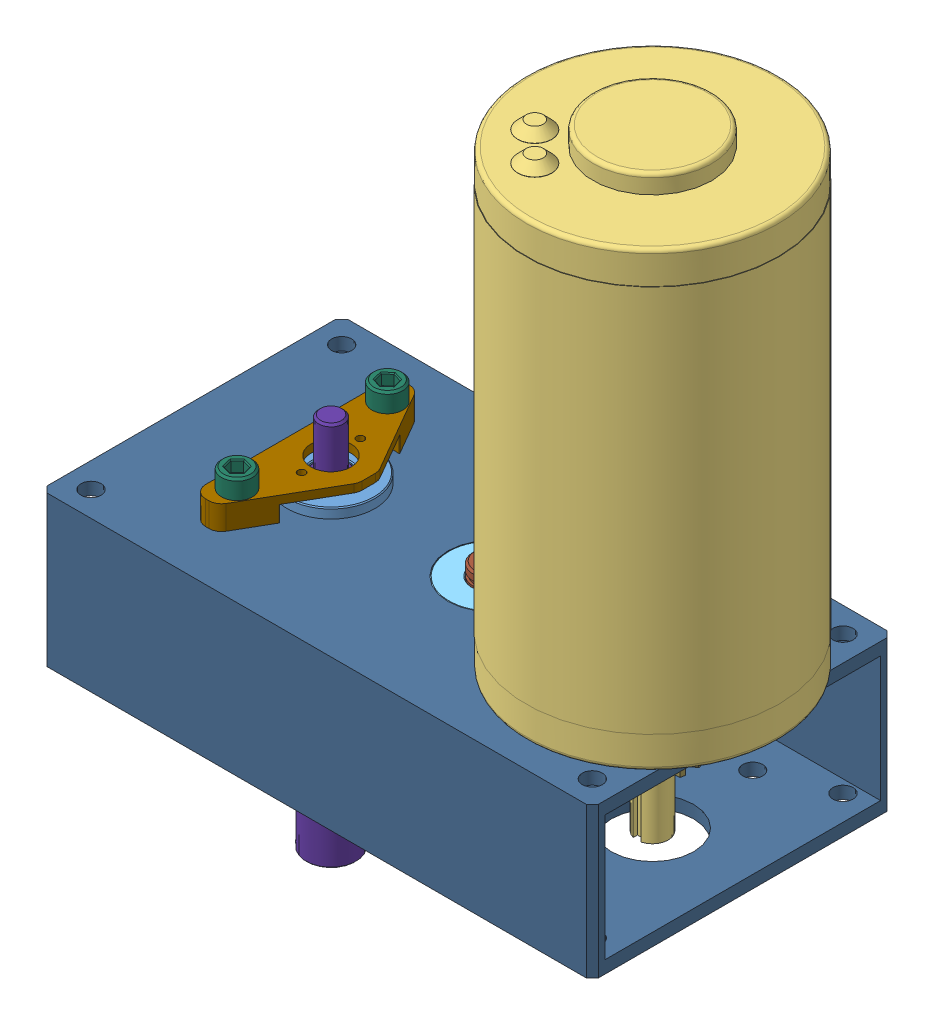
SolidWorks assembly Toughbox Nano 500 key, configuration Default. Lengths in mm.
Overall size (155.61 199.38 84.31).
20 component instances, 17 part files, 0 mates.
Components (placement in the parent):
- fr-6-zz-1: fr-6-zz [Default] at (44.2691 14.351 6.042) x (1 0 0) z (0 1 0) size (24.69 24.69 7.16)
- fr8zz-hex-1: fr8zz-hex [Default] at (35.4076 -22.2783 0) x (0.98361 0 -0.180311) z (0 1 0) size (31.12 31.12 7.93)
- CIM motor-1: CIM motor [Default] at (226.1362 38.1 -35.56) x (0 0 1) z (0 -1 0) size (64.01 64.01 154.95)
- fr-6-zz-hex-1: fr-6-zz-hex [Default] at (84.883 -14.351 -6.1894) x (0.99986 0 -0.016728) z (0 -1 0) size (24.69 24.69 7.75)
- fr-6-1: fr-6 [Default] at (86.7029 13.5128 -1.7646) x (0.722285 0 -0.691595) z (0 1 0) size (24.69 24.69 5.54)
- Toughbox_d05-1: Toughbox_d05 [Default] at (76.1238 3.3528 0) x (-0.016728 0 -0.99986) z (0 1 0) size (65.97 66.04 10.34)
- Toughbox_d08-1: Toughbox_d08 [Default] at (76.1238 3.3528 0) x (0.874268 0 0.485443) z (0 -1 0) size (20.03 20.32 15.25)
- Toughbox_d06-1: Toughbox_d06 [Default] at (35.4076 -0.4318 0) x (0.335651 0 -0.941987) z (0 -1 0) size (65.97 66.04 10.62)
- Toughbox_d29a-1: Toughbox_d29a [Default] at (35.3949 19.05 0) size (19.05 6.1 50.8)
- Toughbox-nano-d01-1: Toughbox-nano-d01 [Default] at origin size (139.7 38.1 76.2)
- Toughbox-nano-d02-1: Toughbox-nano-d02 [Default] at (33.7409 -21.4122 -4.4704) x (-0.874268 0 -0.485443) z (-0.485443 0 0.874268) size (11 43.81 9.52)
- Toughbox_d09-1: Toughbox_d09 [Default] at (116.84 1.524 0) x (-1 0 0) z (0 1 0) size (20.03 20.32 12.7)
- 8mm_spring_clip-1: 8mm_spring_clip [Default] at (116.84 0.5836 0) x (0 1 0) z (0.466354 0 -0.884598) size (1.12 14.83 14.83)
- 2mmx2mmx10mm_key-1: 2mmx2mmx10mm_key [Default] at (119.2442 -2.476 4.8) x (0 1 0) z (1 0 0) size (10 2 2)
- 10-32x0500_shcs-1: 10-32x0500_shcs [Default] at (30.6324 29.9212 19.05) x (0.282005 0 -0.959413) z (0.959413 0 0.282005) size (7.82 17.48 7.82)
- 10-32x0500_shcs-2: 10-32x0500_shcs [Default] at (30.6324 29.9212 -19.05) x (0.282005 0 -0.959413) z (0.959413 0 0.282005) size (7.82 17.48 7.82)
- 10-32x0500_shcs-3: 10-32x0500_shcs [Default] at (116.84 11.0998 -25.4) x (-0.525528 0 0.850777) z (0.850777 0 0.525528) size (7.82 17.48 7.82)
- 10-32x0500_shcs-4: 10-32x0500_shcs [Default] at (116.84 11.0998 25.4) x (-0.525528 0 0.850777) z (0.850777 0 0.525528) size (7.82 17.48 7.82)
- 500-e-klip-1: 500-e-klip [Default] at (35.4076 0.8382 0) x (-0.210896 0 -0.977509) z (0 -1 0) size (19.07 20.96 1.27)
- Toughbox-nano-d04-1: Toughbox-nano-d04 [Default] at (-2.1102 -22.352 -18.3768) x (-0.647959 0 -0.761675) z (-0.761675 0 0.647959) size (14.66 95.12 12.7)
